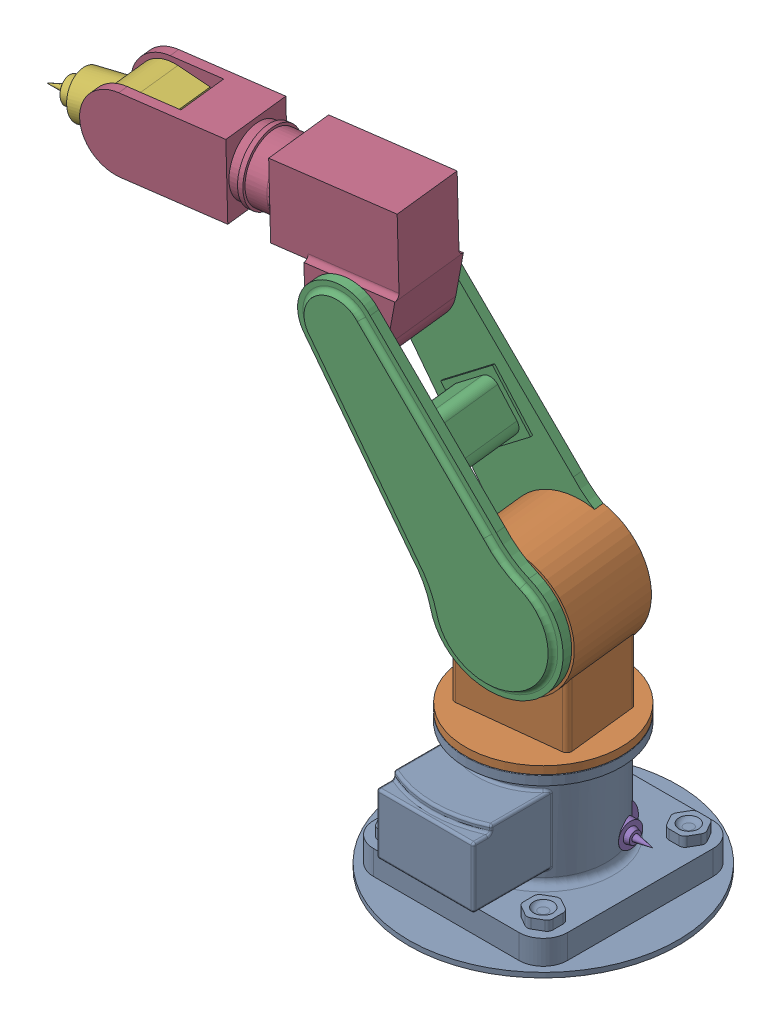
SolidWorks assembly Assem1, configuration Default. Lengths in mm.
Overall size (1205.82 1119.93 555).
6 component instances, 5 part files, 8 mates.
Components (placement in the parent):
- BASE-1: BASE [Default] at (22.2164 -95.7516 53.329) size (555 280 555)
- LINK1-1: LINK1 [Default] at (22.2164 64.2484 53.329) x (-0.993859 0 0.11065) z (-0.11065 0 -0.993859) size (320 466 320)
- LINK2-1: LINK2 [Default] at (23.3229 400.2484 63.2676) x (0.80126 0.591629 -0.089208) z (0.587996 -0.806211 -0.065464) size (250 221.13 700)
- LINK3-1: LINK3 [Default] at (-182.44 949.2027 86.176) x (-0.993566 -0.024278 0.110618) z (-0.11065 0 -0.993859) size (595 296.15 160)
- LINK4-1: LINK4 [Default] at origin size (275 130 100)
- LINK4-4: LINK4 [Default] at (-699.0946 936.5781 143.6973) x (-0.981826 -0.15514 0.109311) z (-0.11065 0 -0.993859) size (275 130 100)
Mates (geometry in assembly coordinates):
- Concentric1: concentric anti-aligned: cylinder of BASE-1 through (22.2164 -15.7516 53.329) axis (0 1 0) radius 100; cylinder of LINK1-1 through (22.2164 184.2484 53.329) axis (0 -1 0) radius 100
- Coincident1: coincident anti-aligned: plane of BASE-1 through (22.2164 184.2484 53.329) normal (0 1 0); plane of LINK1-1 through (22.2164 184.2484 53.329) normal (0 -1 0)
- Concentric2: concentric anti-aligned: cylinder of LINK1-1 through (12.2578 400.2484 -36.1184) axis (0.11065 0 0.993859) radius 75; cylinder of LINK2-1 through (33.2814 400.2484 152.7149) axis (-0.11065 0 -0.993859) radius 75
- Coincident2: coincident aligned: circle of LINK1-1; plane of LINK2-1 through (-261.8229 803.3537 175.5083) normal (-0.11065 0 -0.993859)
- Concentric5: concentric anti-aligned: cylinder of LINK2-1 through (-260.7164 803.3537 185.4469) axis (-0.11065 0 -0.993859) radius 50; cylinder of LINK3-1 through (-279.527 803.3537 16.4908) axis (0.11065 0 0.993859) radius 50
- Coincident3: coincident anti-aligned: plane of LINK2-1 through (-279.527 803.3537 16.4908) normal (0.11065 0 0.993859); plane of LINK3-1 through (-279.527 803.3537 16.4908) normal (-0.11065 0 -0.993859)
- Concentric9: concentric aligned: cylinder of LINK3-1 through (-704.6271 936.5781 94.0043) axis (0.11065 0 0.993859) radius 50; cylinder of LINK4-4 through (-704.6271 936.5781 94.0043) axis (0.11065 0 0.993859) radius 50
- Coincident5: coincident anti-aligned: plane of LINK3-1 through (-693.562 936.5781 193.3903) normal (-0.11065 0 -0.993859); plane of LINK4-4 through (-693.562 936.5781 193.3903) normal (0.11065 0 0.993859)
